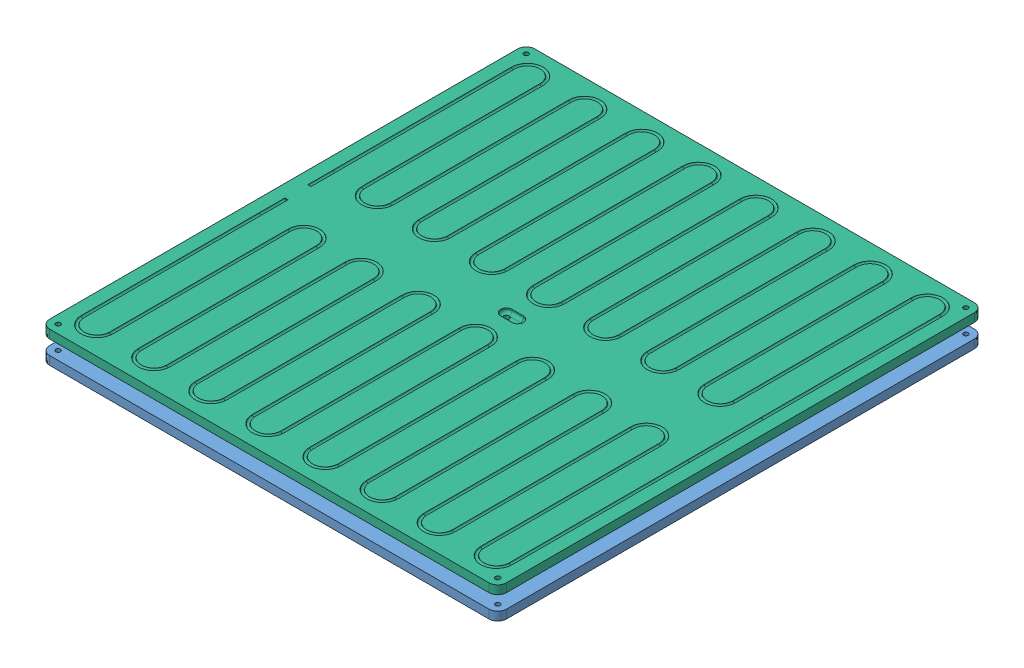
SolidWorks assembly plywood4hot_bed_w_belt_mount, configuration По умолчанию. Lengths in mm.
Overall size (320 86.65 340).
16 component instances, 6 part files, 35 mates.
Components (placement in the parent):
- plywood4hot_bed-1: plywood4hot_bed [По умолчанию] at origin size (320 6 340)
- plywood4belt_mount_plate_triangle-1: plywood4belt_mount_plate_triangle [По умолчанию] at (0 0 -30) size (80 51 6)
- plywood4belt_mount_plate_triangle-2: plywood4belt_mount_plate_triangle [По умолчанию] at (0 0 -4) size (80 51 6)
- DIN967-1: DIN967 [М4х40] at (-9.5 -40 -33.05) x (0 0 1) z (0.923728 0.383049 0) size (42.96 34 34.42)
- DIN967-2: DIN967 [М4х40] at (9.5 -40 5.05) x (0 0 -1) z (-0.706748 0.707465 0) size (42.96 34 34.42)
- DIN 985-8-1: DIN 985-8 [DIN 985 - NUT M4] at (9.5 -40 -30) x (0.383049 -0.923728 0) z (0.923728 0.383049 0) size (7 5.37 8.08)
- DIN 985-8-2: DIN 985-8 [DIN 985 - NUT M4] at (-9.5 -40 2) x (-0.707465 -0.706748 0) z (-0.706748 0.707465 0) size (7 5.37 8.08)
- DIN967-3: DIN967 [M4х16] at (-23 9.05 -27) x (0 -1 0) z (0 0 -1) size (18.96 34 34.42)
- din 562 m4-1: din 562 m4 [По умолчанию] at (-22.9998 -5 -26.9982) x (-1 0 0) z (0 -1 0) size (7 7 2.2)
- DIN967-4: DIN967 [M4х16] at (-23 9.05 -1) x (0 -1 0) z (0 0 1) size (18.96 34 34.42)
- din 562 m4-2: din 562 m4 [По умолчанию] at (-23.0002 -5 -1.0018) x (1 0 0) z (0 -1 0) size (7 7 2.2)
- DIN967-5: DIN967 [M4х16] at (23 9.05 -27) x (0 -1 0) z (0 0 -1) size (18.96 34 34.42)
- din 562 m4-3: din 562 m4 [По умолчанию] at (23.0002 -5 -26.9982) x (-1 0 0) z (0 -1 0) size (7 7 2.2)
- DIN967-6: DIN967 [M4х16] at (23 9.05 -1) x (0 -1 0) z (0 0 1) size (18.96 34 34.42)
- din 562 m4-4: din 562 m4 [По умолчанию] at (22.9998 -5 -1.0018) x (1 0 0) z (0 -1 0) size (7 7 2.2)
- plywood4hot_bed_w_snake-1: plywood4hot_bed_w_snake [По умолчанию] at (0 16 0) size (320 6 340)
Mates (geometry in assembly coordinates):
- Совпадение1: coincident anti-aligned: plane of plywood4hot_bed-1 through (-154 0 150) normal (0 -1 0); plane of plywood4belt_mount_plate_triangle-1 through (-40 0 -24) normal (0 1 0)
- Совпадение3: coincident anti-aligned: plane of plywood4hot_bed-1 through (-154 0 150) normal (0 -1 0); plane of plywood4belt_mount_plate_triangle-2 through (-40 0 2) normal (0 1 0)
- Концентричный1: concentric aligned: cylinder of plywood4belt_mount_plate_triangle-1 through (-9.5 -40 -24) axis (0 0 -1) radius 2.05; cylinder of DIN967-1 through (-9.5 -40 -39.4) axis (0 0 -1) radius 2
- Совпадение4: coincident anti-aligned: plane of plywood4belt_mount_plate_triangle-1 through (9.5 -40 -30) normal (0 0 -1); plane of DIN967-1 through (-8.7339 -41.8475 -30) normal (0 0 1)
- Концентричный2: concentric aligned: cylinder of plywood4belt_mount_plate_triangle-2 through (-9.5 -40 2) axis (0 0 -1) radius 2.05; cylinder of DIN967-1 through (-9.5 -40 -39.4) axis (0 0 -1) radius 2
- Концентричный3: concentric anti-aligned: cylinder of plywood4belt_mount_plate_triangle-2 through (9.5 -40 2) axis (0 0 -1) radius 2.05; cylinder of DIN967-2 through (9.5 -40 11.4) axis (0 0 1) radius 2
- Совпадение5: coincident anti-aligned: plane of plywood4belt_mount_plate_triangle-2 through (9.5 -40 2) normal (0 0 1); plane of DIN967-2 through (8.0851 -41.4135 2) normal (0 0 -1)
- Расстояние1: distance = 20 mm anti-aligned: plane of plywood4belt_mount_plate_triangle-2 through (9.5 -40 -4) normal (0 0 -1); plane of plywood4belt_mount_plate_triangle-1 through (9.5 -40 -24) normal (0 0 1)
- Совпадение7: coincident anti-aligned: plane of plywood4belt_mount_plate_triangle-1 through (9.5 -40 -30) normal (0 0 -1); plane of DIN 985-8-1 through (11.3475 -39.2339 -30) normal (0 0 1)
- Концентричный4: concentric anti-aligned: cylinder of DIN967-2 through (9.5 -40 11.4) axis (0 0 1) radius 2; circle of DIN 985-8-1
- Совпадение8: coincident anti-aligned: plane of plywood4belt_mount_plate_triangle-2 through (9.5 -40 2) normal (0 0 1); plane of DIN 985-8-2 through (-10.9135 -38.5851 2) normal (0 0 -1)
- Концентричный5: concentric anti-aligned: cylinder of DIN967-1 through (-9.5 -40 -39.4) axis (0 0 -1) radius 2; cylinder of DIN 985-8-2 through (-9.5 -40 2) axis (0 0 1) radius 1.65
- Совпадение91: coincident anti-aligned: plane of plywood4hot_bed-1 through (-154 6 150) normal (0 1 0); plane of DIN967-3 through (-25 6 -27) normal (0 -1 0)
- Совпадение10: coincident anti-aligned: plane of plywood4belt_mount_plate_triangle-1 through (9.5 -40 -30) normal (0 0 -1); plane of DIN967-3 through (-23 9.05 -30) normal (0 0 1)
- Совпадение11: coincident: line of plywood4belt_mount_plate_triangle-1 through (-40 0 -24) axis (0 0 -1); plane of DIN967-3 through (-40 9.05 -27) normal (1 0 0)
- Концентричный8: concentric anti-aligned: cylinder of DIN967-3 through (-23 15.4 -27) axis (0 1 0) radius 2; cylinder of din 562 m4-1 through (-23 -5 -27) axis (0 -1 0) radius 2
- Совпадение12: coincident anti-aligned: plane of din 562 m4-1 through (-22.9998 -5 -26.9982) normal (0 1 0); plane of plywood4belt_mount_plate_triangle-1 through (-20.9 -5 -24) normal (0 -1 0)
- Совпадение131: coincident anti-aligned: plane of plywood4hot_bed-1 through (-154 6 150) normal (0 1 0); plane of DIN967-4 through (-21 6 -1) normal (0 -1 0)
- Совпадение14: coincident anti-aligned: plane of plywood4belt_mount_plate_triangle-2 through (9.5 -40 2) normal (0 0 1); plane of DIN967-4 through (-23 9.05 2) normal (0 0 -1)
- Совпадение15: coincident: line of plywood4belt_mount_plate_triangle-2 through (-40 0 2) axis (0 0 -1); plane of DIN967-4 through (-40 9.05 -1) normal (1 0 0)
- Концентричный11: concentric anti-aligned: cylinder of DIN967-4 through (-23 15.4 -1) axis (0 1 0) radius 2; cylinder of din 562 m4-2 through (-23 -5 -1) axis (0 -1 0) radius 2
- Совпадение161: coincident anti-aligned: plane of plywood4hot_bed-1 through (-154 6 150) normal (0 1 0); plane of DIN967-5 through (21 6 -27) normal (0 -1 0)
- Совпадение17: coincident anti-aligned: plane of plywood4belt_mount_plate_triangle-1 through (9.5 -40 -30) normal (0 0 -1); plane of DIN967-5 through (23 9.05 -30) normal (0 0 1)
- Совпадение18: coincident: line of plywood4belt_mount_plate_triangle-1 through (40 0 -24) axis (0 0 -1); plane of DIN967-5 through (40 9.05 -27) normal (-1 0 0)
- Концентричный14: concentric anti-aligned: cylinder of DIN967-5 through (23 15.4 -27) axis (0 1 0) radius 2; cylinder of din 562 m4-3 through (23 -5 -27) axis (0 -1 0) radius 2
- Совпадение19: coincident anti-aligned: plane of din 562 m4-3 through (23.0002 -5 -26.9982) normal (0 1 0); plane of plywood4belt_mount_plate_triangle-1 through (25.1 -5 -24) normal (0 -1 0)
- Совпадение201: coincident anti-aligned: plane of plywood4hot_bed-1 through (-154 6 150) normal (0 1 0); plane of DIN967-6 through (25 6 -1) normal (0 -1 0)
- Совпадение21: coincident anti-aligned: plane of plywood4belt_mount_plate_triangle-2 through (9.5 -40 2) normal (0 0 1); plane of DIN967-6 through (23 9.05 2) normal (0 0 -1)
- Совпадение22: coincident aligned: plane of DIN967-5 through (40 9.05 -27) normal (-1 0 0); plane of DIN967-6 through (40 9.05 -1) normal (-1 0 0)
- Концентричный19: concentric anti-aligned: cylinder of DIN967-6 through (23 15.4 -1) axis (0 1 0) radius 2; cylinder of din 562 m4-4 through (23 -5 -1) axis (0 -1 0) radius 2
- Расстояние2: distance = 10 mm anti-aligned: plane of plywood4belt_mount_plate_triangle-1 through (9.5 -40 -24) normal (0 0 1); plane of plywood4hot_bed-1 through (0 0 -14) normal (0 0 -1)
- Совпадение25: coincident anti-aligned: plane of plywood4hot_bed-1 through (0 0 0) normal (-1 0 0); plane of plywood4belt_mount_plate_triangle-2 through (0 0 -4) normal (1 0 0)
- Расстояние3: distance = 10 mm anti-aligned: plane of plywood4hot_bed_w_snake-1 through (-154 16 150) normal (0 -1 0); plane of plywood4hot_bed-1 through (-154 6 150) normal (0 1 0)
- Совпадение203: coincident aligned: plane of plywood4hot_bed-1 through (160 6 150) normal (1 0 0); plane of plywood4hot_bed_w_snake-1 through (160 22 150) normal (1 0 0)
- Совпадение204: coincident aligned: plane of plywood4hot_bed-1 through (-154 6 156) normal (0 0 1); plane of plywood4hot_bed_w_snake-1 through (-154 22 156) normal (0 0 1)
